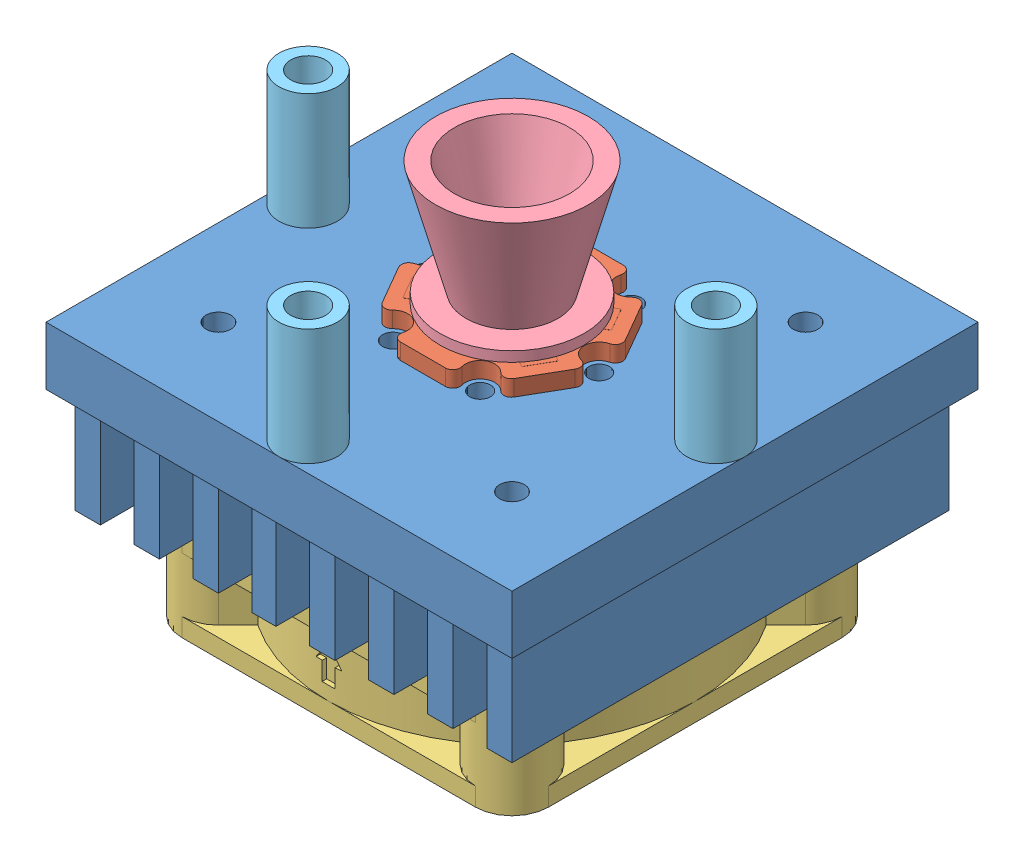
SolidWorks assembly Retina Fucker-No Peltier, configuration Default. Lengths in mm.
Overall size (50.8 43.67 52.39).
7 component instances, 5 part files, 15 mates.
Components (placement in the parent):
- LED Interface Plate-No Peltier-1: LED Interface Plate-No Peltier [Default] at (13.1908 22.1092 31.2346) size (50.8 17.78 52.39)
- LZ4-40G108-0000-1: LZ4-40G108-0000 [Default] at (13.1908 28.4592 31.2346) size (19.46 5.4 19.4)
- 1939K170_DC EQUIPMENT COOLING FAN-1: 1939K170_DC EQUIPMENT COOLING FAN [Default] at (13.1908 10.6792 31.2346) x (1 0 0) z (0 -1 0) size (40 40 10.64)
- Reflector-1: Reflector [Default] at (13.1908 30.2092 31.2346) x (0.991681 0 -0.128723) z (0.128723 0 0.991681) size (16.67 13.5 16.67)
- Front Mounting Spacer-1: Front Mounting Spacer [Default] at (-9.0342 28.4592 31.2346) x (1 0 0) z (0 1 0) size (6.35 6.35 12.7)
- Front Mounting Spacer-2: Front Mounting Spacer [Default] at (13.1908 28.4592 53.4596) x (1 0 0) z (0 1 0) size (6.35 6.35 12.7)
- Front Mounting Spacer-3: Front Mounting Spacer [Default] at (35.4158 28.4592 31.2346) x (1 0 0) z (0 1 0) size (6.35 6.35 12.7)
Mates (geometry in assembly coordinates):
- Coincident1: coincident anti-aligned: plane of LED Interface Plate-No Peltier-1 through (13.1908 28.4592 31.2346) normal (0 1 0); plane of LZ4-40G108-0000-1 through (13.1908 28.4592 31.2346) normal (0 -1 0)
- Concentric1: concentric aligned: cylinder of LED Interface Plate-No Peltier-1 through (17.9408 28.4592 39.4619) axis (0 1 0) radius 1.1303; cylinder of LZ4-40G108-0000-1 through (17.9408 28.4592 39.4619) axis (0 1 0) radius 1.6
- Concentric2: concentric aligned: cylinder of LED Interface Plate-No Peltier-1 through (8.4408 28.4592 39.4619) axis (0 1 0) radius 1.1303; cylinder of LZ4-40G108-0000-1 through (8.4408 28.4592 39.4619) axis (0 1 0) radius 1.6
- Coincident9: coincident aligned: line of LED Interface Plate-No Peltier-1 through (13.1908 22.1092 31.2346) axis (0 -1 0); axis of 1939K170_DC EQUIPMENT COOLING FAN-1 through (13.1908 8.6792 31.2346) axis (0 -1 0)
- Concentric9: concentric aligned: circle of LZ4-40G108-0000-1; axis of Reflector-1 through (13.1908 43.7092 31.2346) axis (0 -1 0)
- Coincident12: coincident anti-aligned: plane of LZ4-40G108-0000-1 through (13.1908 30.2092 31.2346) normal (0 1 0); plane of Reflector-1 through (17.3261 30.2092 30.6978) normal (0 -1 0)
- Coincident13: coincident anti-aligned: plane of LED Interface Plate-No Peltier-1 through (13.1908 28.4592 31.2346) normal (0 1 0); plane of Front Mounting Spacer-3 through (35.4158 28.4592 31.2346) normal (0 -1 0)
- Coincident14: coincident anti-aligned: plane of LED Interface Plate-No Peltier-1 through (13.1908 28.4592 31.2346) normal (0 1 0); plane of Front Mounting Spacer-2 through (13.1908 28.4592 53.4596) normal (0 -1 0)
- Coincident15: coincident anti-aligned: plane of LED Interface Plate-No Peltier-1 through (13.1908 28.4592 31.2346) normal (0 1 0); plane of Front Mounting Spacer-1 through (-9.0342 28.4592 31.2346) normal (0 -1 0)
- Concentric10: concentric anti-aligned: circle of LED Interface Plate-No Peltier-1; cylinder of Front Mounting Spacer-1 through (-9.0342 41.1592 31.2346) axis (0 -1 0) radius 3.175
- Concentric11: concentric anti-aligned: circle of LED Interface Plate-No Peltier-1; cylinder of Front Mounting Spacer-2 through (13.1908 41.1592 53.4596) axis (0 -1 0) radius 3.175
- Concentric12: concentric anti-aligned: cylinder of LED Interface Plate-No Peltier-1 through (35.4158 28.4592 31.2346) axis (0 1 0) radius 1.3526; cylinder of Front Mounting Spacer-3 through (35.4158 41.1592 31.2346) axis (0 -1 0) radius 3.175
- Coincident16: coincident anti-aligned: plane of LED Interface Plate-No Peltier-1 through (13.1908 10.6792 31.2346) normal (0 -1 0); plane of 1939K170_DC EQUIPMENT COOLING FAN-1 through (29.1908 10.6792 15.2346) normal (0 1 0)
- Parallel1: parallel anti-aligned: cylinder of LED Interface Plate-No Peltier-1 through (-2.8112 10.6792 47.2366) axis (0 -1 0) radius 1.3526; cylinder of 1939K170_DC EQUIPMENT COOLING FAN-1 through (-2.8092 0.6792 47.2346) axis (0 1 0) radius 1.778
- Parallel2: parallel anti-aligned: cylinder of LED Interface Plate-No Peltier-1 through (29.1928 10.6792 47.2366) axis (0 -1 0) radius 1.3526; cylinder of 1939K170_DC EQUIPMENT COOLING FAN-1 through (29.1908 0.6792 47.2346) axis (0 1 0) radius 1.778
